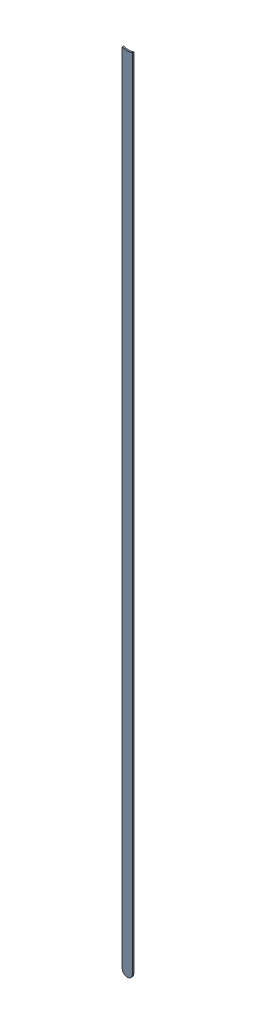
SolidWorks assembly Track (11.2mm,10.1mm)(11.2mm,30.4mm) on Top Layer, configuration Predeterminado. Lengths in mm.
Overall size (0.25 20.09 0.04).
2 component instances, 1 part files, 0 mates.
Components (placement in the parent):
- Track (11.2mm,10.1mm)(11.2mm,30.4mm) on Top Layer-1-1: Track (11.2mm,10.1mm)(11.2mm,30.4mm) on Top Layer-1 [Predeterminado] at (-68.317 -44.187 -0.0457) size (0.25 20.09 0.04)
  - Track (11.2mm,10.1mm)(11.2mm,30.4mm) on Top Layer-Part-1-1: Track (11.2mm,10.1mm)(11.2mm,30.4mm) on Top Layer-Part-1 [Predeterminado] at origin size (0.25 20.09 0.04)
